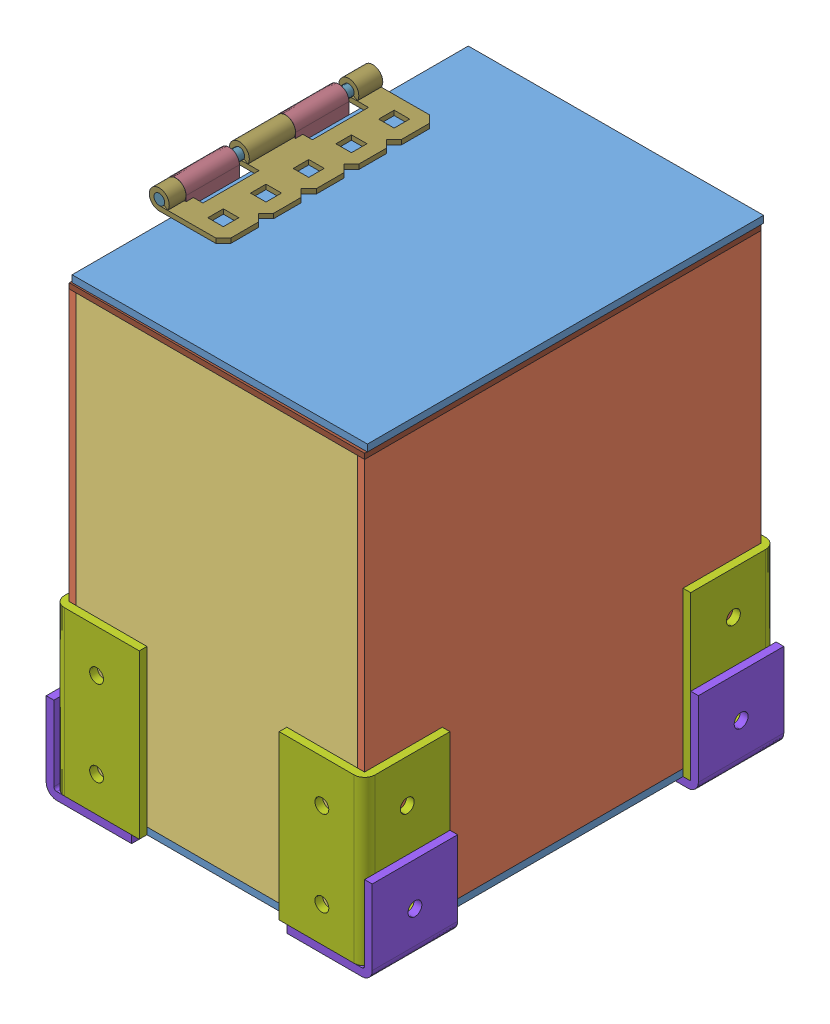
SolidWorks assembly Brain Box, configuration Default. Lengths in mm.
Overall size (98.42 141.04 122.4).
24 component instances, 15 part files, 51 mates.
Components (placement in the parent):
- Bottom Brain Box Plate-1: Bottom Brain Box Plate [Default] at origin size (87.83 2.03 117.83)
- Side Brain Box Plate-2: Side Brain Box Plate [Default] at (85.796 0 4.572) size (2.03 127 117.83)
- Brain Box Front Plate-1: Brain Box Front Plate [Default] at origin
- Side Brain Box Plate-3: Side Brain Box Plate [Default] at (0 0 4.572) size (2.03 127 117.83)
- Brain Box Front Plate Real-1: Brain Box Front Plate Real [Default] at origin size (83.76 127 2.03)
- Brain Box Front Plate Real-2: Brain Box Front Plate Real [Default] at (0 0 -115.796) size (83.76 127 2.03)
- Breadboard-1: Breadboard [Default] at (85.796 18.0502 -33.0464) x (0 1 0) z (0 0 1) size (86.36 9.65 55.88)
- ESP Breakout-1: ESP Breakout [Default] at (76.144 55.9536 -42.2125) x (0 1 0) z (0 0 1) size (38 5 25)
- TSR12450-1: TSR12450 [Default] at (65.944 80.1193 -73.0785) x (0 -1 0) z (0 0 1) size (11.7 10.2 7.6)
- Brain Box Connector-12: Brain Box Connector [Default] at (-2.286 -624.586 2.286) x (0 0 -1) z (0 -1 0) size (25.4 25.4 48.51)
- Brain Box Connector 1in-6: Brain Box Connector 1in [Default] at (-4.572 -2.286 649.986) size (25.4 25.4 25.4)
- Brain Box Connector-13: Brain Box Connector [Default] at (-2.286 -624.586 -120.114) x (1 0 0) z (0 -1 0) size (25.4 25.4 48.51)
- Brain Box Connector 1in-7: Brain Box Connector 1in [Default] at (-4.572 -2.286 552.986) size (25.4 25.4 25.4)
- Brain Box Connector-14: Brain Box Connector [Default] at (90.114 -624.586 -120.114) x (0 0 1) z (0 -1 0) size (25.4 25.4 48.51)
- Brain Box Connector 1in-8: Brain Box Connector 1in [Default] at (92.4 -2.286 -767.814) x (-1 0 0) z (0 0 -1) size (25.4 25.4 25.4)
- Brain Box Connector-15: Brain Box Connector [Default] at (90.114 -624.586 2.286) x (-1 0 0) z (0 -1 0) size (25.4 25.4 48.51)
- Brain Box Connector 1in-9: Brain Box Connector 1in [Default] at (92.4 -2.286 -670.814) x (-1 0 0) z (0 0 -1) size (25.4 25.4 25.4)
- Fuse Box-1: Fuse Box [Default] at (7.9055 2.032 -40.132) x (1 0 0) z (0 -1 0) size (63.5 38.1 86.36)
- Battery-1: Battery [Default] at (30.032 2.032 -94.6088) x (0 0 1) z (0 -1 0) size (36 28 107)
- Brain Box Dust Protector-1: Brain Box Dust Protector [Default] at origin size (87.83 1.59 117.83)
- Hinge Part 1-1: Hinge Part 1 [Default] at (12.8755 132.7707 -61.5286) x (0.999994 0.003505 0) z (0 0 1) size (22.03 5.97 63.5)
- Hinge Part 2-1: Hinge Part 2 [Default] at (0 119.8245 -58.9719) x (0 -1 0) z (0 0 -1) size (22.06 6.02 63.5)
- Hinge Pin-1: Hinge Pin [Default] at (-3.0099 135.6995 -93.2786) size (3.17 3.17 63.5)
- Bottom Brain Box Plate-2: Bottom Brain Box Plate [Default] at (0.4687 130.6952 -0.3832) x (0.999994 0.003505 0) z (0 0 1) size (87.83 2.03 117.83)
Mates (geometry in assembly coordinates):
- Coincident1: coincident anti-aligned: plane of Bottom Brain Box Plate-1 through (0 2.032 0) normal (0 1 0); plane of Side Brain Box Plate-2 through (87.828 2.032 -117.828) normal (0 -1 0)
- Coincident2: coincident aligned: plane of Bottom Brain Box Plate-1 through (0 2.032 0) normal (0 0 1); plane of Side Brain Box Plate-2 through (87.828 2.032 0) normal (0 0 1)
- Coincident3: coincident aligned: plane of Bottom Brain Box Plate-1 through (87.828 2.032 0) normal (1 0 0); plane of Side Brain Box Plate-2 through (87.828 0 4.572) normal (1 0 0)
- Coincident9: coincident anti-aligned: plane of Bottom Brain Box Plate-1 through (0 2.032 0) normal (0 1 0); plane of Side Brain Box Plate-3 through (2.032 2.032 -117.828) normal (0 -1 0)
- Coincident10: coincident aligned: plane of Bottom Brain Box Plate-1 through (0 2.032 0) normal (0 0 1); plane of Side Brain Box Plate-3 through (2.032 2.032 0) normal (0 0 1)
- Coincident11: coincident aligned: plane of Bottom Brain Box Plate-1 through (0 2.032 0) normal (-1 0 0); plane of Side Brain Box Plate-3 through (0 0 4.572) normal (-1 0 0)
- Coincident15: coincident anti-aligned: plane of Bottom Brain Box Plate-1 through (0 2.032 0) normal (0 1 0); plane of Brain Box Front Plate Real-2 through (2.032 2.032 -117.828) normal (0 -1 0)
- Coincident16: coincident anti-aligned: plane of Side Brain Box Plate-3 through (2.032 0 4.572) normal (1 0 0); plane of Brain Box Front Plate Real-2 through (2.032 2.032 -117.828) normal (-1 0 0)
- Coincident17: coincident anti-aligned: line of Side Brain Box Plate-3 through (2.032 2.032 -117.828) axis (0 1 0); line of Brain Box Front Plate Real-2 through (2.032 129.032 -117.828) axis (0 -1 0)
- Coincident62: coincident anti-aligned: plane of Side Brain Box Plate-2 through (85.796 0 4.572) normal (-1 0 0); plane of Breadboard-1 through (85.796 18.0502 -33.0464) normal (1 0 0)
- Coincident64: coincident anti-aligned: plane of Side Brain Box Plate-2 through (85.796 0 4.572) normal (-1 0 0); plane of Breadboard-1 through (85.796 18.0502 -33.0464) normal (1 0 0)
- Coincident66: coincident anti-aligned: plane of Breadboard-1 through (76.144 18.0502 -33.0464) normal (-1 0 0); plane of ESP Breakout-1 through (76.144 55.9536 -42.2125) normal (1 0 0)
- Coincident67: coincident anti-aligned: plane of Breadboard-1 through (76.144 18.0502 -33.0464) normal (-1 0 0); plane of TSR12450-1 through (76.144 80.1193 -73.0785) normal (1 0 0)
- Coincident69: coincident anti-aligned: plane of Brain Box Front Plate Real-1 through (0 0 0) normal (0 0 1); plane of Brain Box Connector-12 through (0 -1373.886 0) normal (0 0 -1)
- Coincident77: coincident anti-aligned: plane of Brain Box Front Plate Real-1 through (0 0 0) normal (0 0 1); plane of Brain Box Connector-12 through (0 -1373.886 0) normal (0 0 -1)
- Coincident78: coincident anti-aligned: plane of Side Brain Box Plate-3 through (0 0 4.572) normal (-1 0 0); plane of Brain Box Connector-12 through (0 -1373.886 -23.114) normal (1 0 0)
- Concentric10: concentric aligned: cylinder of Brain Box Connector-12 through (-2.286 10.414 -10.414) axis (-1 0 0) radius 2.0701; cylinder of Brain Box Connector 1in-6 through (-4.572 10.414 -10.414) axis (-1 0 0) radius 2.0701
- Coincident79: coincident anti-aligned: plane of Bottom Brain Box Plate-1 through (0 0 0) normal (0 -1 0); plane of Brain Box Connector 1in-6 through (20.828 0 1399.286) normal (0 1 0)
- Coincident80: coincident anti-aligned: plane of Brain Box Connector-12 through (-2.286 124.714 -23.114) normal (-1 0 0); plane of Brain Box Connector 1in-6 through (-2.286 0 1399.286) normal (1 0 0)
- Coincident81: coincident anti-aligned: plane of Side Brain Box Plate-3 through (0 0 4.572) normal (-1 0 0); plane of Brain Box Connector-13 through (0 -1373.886 -117.828) normal (1 0 0)
- Coincident82: coincident anti-aligned: plane of Brain Box Front Plate Real-2 through (0 0 -117.828) normal (0 0 -1); plane of Brain Box Connector-13 through (23.114 -1373.886 -117.828) normal (0 0 1)
- Coincident83: coincident aligned: plane of Bottom Brain Box Plate-1 through (0 0 0) normal (0 -1 0); plane of Brain Box Connector-13 through (-2.286 0 -120.114) normal (0 -1 0)
- Concentric14: concentric aligned: cylinder of Brain Box Connector-13 through (-2.286 10.414 -107.414) axis (-1 0 0) radius 2.0701; cylinder of Brain Box Connector 1in-7 through (-4.572 10.414 -107.414) axis (-1 0 0) radius 2.0701
- Coincident87: coincident anti-aligned: plane of Brain Box Connector-13 through (-2.286 -624.586 -120.114) normal (-1 0 0); plane of Brain Box Connector 1in-7 through (-2.286 0 1302.286) normal (1 0 0)
- Coincident88: coincident anti-aligned: plane of Bottom Brain Box Plate-1 through (0 0 0) normal (0 -1 0); plane of Brain Box Connector 1in-7 through (20.828 0 1302.286) normal (0 1 0)
- Coincident91: coincident aligned: plane of Bottom Brain Box Plate-1 through (0 0 0) normal (0 -1 0); plane of Brain Box Connector-14 through (90.114 0 -120.114) normal (0 -1 0)
- Coincident92: coincident anti-aligned: plane of Brain Box Front Plate Real-2 through (0 0 -117.828) normal (0 0 -1); plane of Brain Box Connector-14 through (87.828 -1373.886 -117.828) normal (0 0 1)
- Coincident93: coincident anti-aligned: plane of Side Brain Box Plate-2 through (87.828 0 4.572) normal (1 0 0); plane of Brain Box Connector-14 through (87.828 -1373.886 -94.714) normal (-1 0 0)
- Concentric15: concentric aligned: cylinder of Brain Box Connector-14 through (90.114 10.414 -107.414) axis (1 0 0) radius 2.0701; cylinder of Brain Box Connector 1in-8 through (92.4 10.414 -107.414) axis (1 0 0) radius 2.0701
- Coincident95: coincident anti-aligned: plane of Bottom Brain Box Plate-1 through (0 0 0) normal (0 -1 0); plane of Brain Box Connector 1in-8 through (67 0 -1517.114) normal (0 1 0)
- Coincident96: coincident anti-aligned: plane of Brain Box Connector-14 through (90.114 124.714 -94.714) normal (1 0 0); plane of Brain Box Connector 1in-8 through (90.114 0 -1517.114) normal (-1 0 0)
- Coincident99: coincident aligned: plane of Bottom Brain Box Plate-1 through (0 0 0) normal (0 -1 0); plane of Brain Box Connector-15 through (90.114 0 2.286) normal (0 -1 0)
- Coincident100: coincident anti-aligned: plane of Brain Box Front Plate Real-1 through (0 0 0) normal (0 0 1); plane of Brain Box Connector-15 through (64.714 -1373.886 0) normal (0 0 -1)
- Coincident101: coincident anti-aligned: plane of Side Brain Box Plate-2 through (87.828 0 4.572) normal (1 0 0); plane of Brain Box Connector-15 through (87.828 -1373.886 0) normal (-1 0 0)
- Concentric16: concentric aligned: cylinder of Brain Box Connector-15 through (90.114 10.414 -10.414) axis (1 0 0) radius 2.0701; cylinder of Brain Box Connector 1in-9 through (92.4 10.414 -10.414) axis (1 0 0) radius 2.0701
- Coincident102: coincident anti-aligned: plane of Bottom Brain Box Plate-1 through (0 0 0) normal (0 -1 0); plane of Brain Box Connector 1in-9 through (67 0 -1420.114) normal (0 1 0)
- Coincident103: coincident anti-aligned: plane of Brain Box Connector-15 through (90.114 -624.586 2.286) normal (1 0 0); plane of Brain Box Connector 1in-9 through (90.114 0 -1420.114) normal (-1 0 0)
- Coincident104: coincident anti-aligned: plane of Brain Box Front Plate Real-1 through (0 0 -2.032) normal (0 0 -1); plane of Fuse Box-1 through (7.9055 2.032 -2.032) normal (0 0 1)
- Coincident105: coincident anti-aligned: plane of Bottom Brain Box Plate-1 through (0 2.032 0) normal (0 1 0); plane of Fuse Box-1 through (7.9055 2.032 -2.032) normal (0 -1 0)
- Coincident106: coincident anti-aligned: plane of Side Brain Box Plate-3 through (2.032 0 4.572) normal (1 0 0); plane of Battery-1 through (2.032 2.032 -94.6088) normal (-1 0 0)
- Coincident107: coincident anti-aligned: plane of Bottom Brain Box Plate-1 through (0 2.032 0) normal (0 1 0); plane of Battery-1 through (2.032 2.032 -94.6088) normal (0 -1 0)
- Concentric17: concentric anti-aligned: cylinder of Hinge Part 1-1 through (-3.0099 135.6995 -80.771) axis (0 0 1) radius 1.5875; cylinder of Hinge Part 2-1 through (-3.0099 135.6995 -34.753) axis (0 0 -1) radius 1.5875
- Coincident114: coincident anti-aligned: plane of Side Brain Box Plate-3 through (0 0 4.572) normal (-1 0 0); plane of Hinge Part 2-1 through (0 135.6995 -90.7219) normal (1 0 0)
- Concentric18: concentric anti-aligned: cylinder of Hinge Part 1-1 through (-3.0099 135.6995 -46.3416) axis (0 0 1) radius 1.5875; cylinder of Hinge Pin-1 through (-3.0099 135.6995 -29.7786) axis (0 0 -1) radius 1.5875
- Coincident115: coincident aligned: plane of Hinge Part 1-1 through (-3.0043 134.112 -29.7786) normal (0 0 1); plane of Hinge Pin-1 through (-1.4224 135.6995 -29.7786) normal (0 0 1)
- Distance2: distance = 27.2219 mm aligned: plane of Hinge Part 2-1 through (0 119.8245 -27.2219) normal (0 0 1); plane of Brain Box Front Plate Real-1 through (0 0 0) normal (0 0 1)
- Distance3: distance = 29.7786 mm aligned: plane of Hinge Part 1-1 through (-3.0043 134.112 -29.7786) normal (0 0 1); plane of Brain Box Front Plate Real-1 through (0 0 0) normal (0 0 1)
- Coincident118: coincident anti-aligned: plane of Hinge Part 1-1 through (-2.9994 132.715 -29.7786) normal (0.003505 -0.999994 0); plane of Bottom Brain Box Plate-2 through (0.4616 132.7271 -0.3832) normal (-0.003505 0.999994 0)
- Distance4: distance = 11.5503 mm aligned: plane of Bottom Brain Box Plate-2 through (0.4616 132.7271 -0.3832) normal (-0.999994 -0.003505 0); plane of Hinge Part 1-1 through (12.0119 132.7675 -33.8172) normal (-0.999994 -0.003505 0)
- Distance5: distance = 13.97 mm anti-aligned: plane of Brain Box Dust Protector-1 through (0 130.6195 0) normal (0 1 0); plane of Hinge Part 2-1 through (0 116.6495 -90.7219) normal (0 -1 0)
- Distance6: distance = 29.3953 mm aligned: plane of Hinge Part 1-1 through (-3.0043 134.112 -29.7786) normal (0 0 1); plane of Bottom Brain Box Plate-2 through (0.4616 132.7271 -0.3832) normal (0 0 1)
